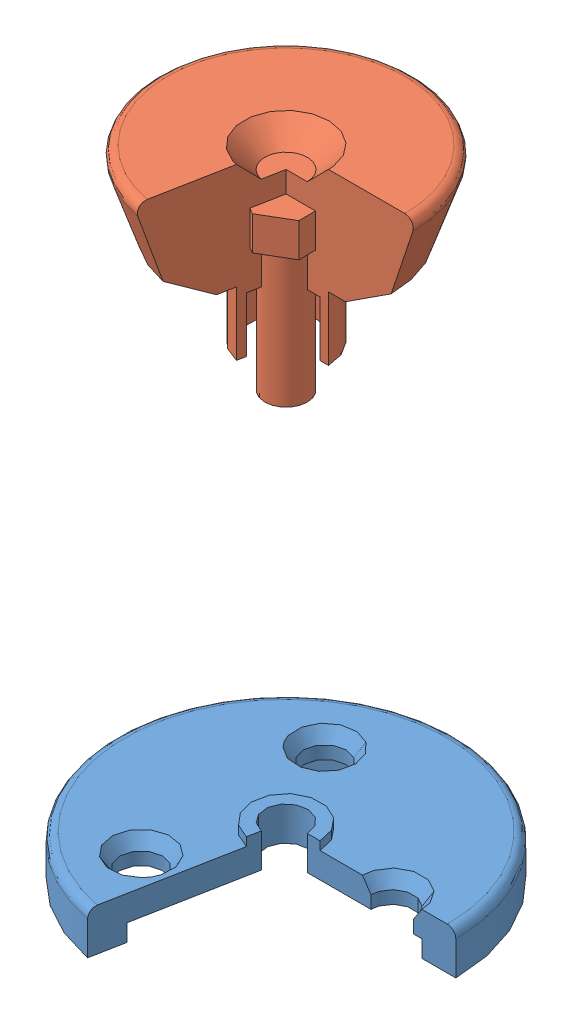
SolidWorks assembly one_ass, configuration По умолчанию. Lengths in mm.
Overall size (80 160 79.29).
2 component instances, 2 part files, 3 mates.
Components (placement in the parent):
- one-1: one [По умолчанию] at (0 -30 0.3543) size (80 60 79.29)
- two-1: two [По умолчанию] at (0 70 0.3543) size (60 60 59.47)
Mates (geometry in assembly coordinates):
- Расстояние1: distance = 0 mm: plane of one-1 through (0 -30 0.3543) normal (1 0 0); plane of two-1 through (0 70 0.3543) normal (1 0 0)
- Расстояние2: distance = 0 mm: plane of one-1 through (0 -30 0.3543) normal (0 0 1); plane of two-1 through (0 70 0.3543) normal (0 0 1)
- Расстояние3: distance = 100 mm aligned: plane of one-1 through (0 -30 0.3543) normal (0 1 0); plane of two-1 through (0 70 0.3543) normal (0 1 0)
